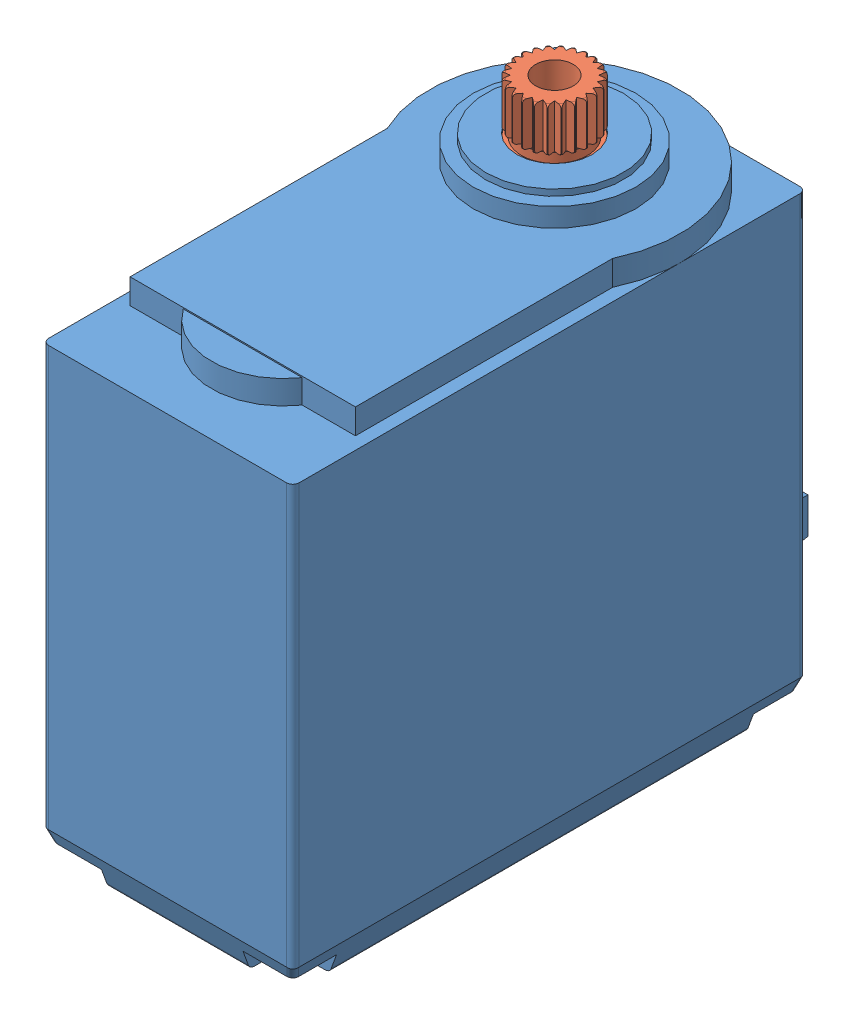
SolidWorks assembly MG996R-ServoMotor, configuration Default. Lengths in mm.
Overall size (20 44.02 48).
2 component instances, 2 part files, 2 mates.
Components (placement in the parent):
- MG996R-ServoMotor-1: MG996R-ServoMotor [Default] at (5.2376 21.8785 43.4533) size (20 40 48)
- MG996R-Gear-1: MG996R-Gear [Default] at (5.3909 -12.8534 33.0533) size (6 6.02 6)
Mates (geometry in assembly coordinates):
- Coincident1: coincident anti-aligned: plane of MG996R-ServoMotor-1 through (5.2376 41.8785 43.4533) normal (0 1 0); plane of MG996R-Gear-1 through (15.2376 41.8785 33.0533) normal (0 -1 0)
- Coincident2: coincident anti-aligned: circle of MG996R-ServoMotor-1; circle of MG996R-Gear-1
